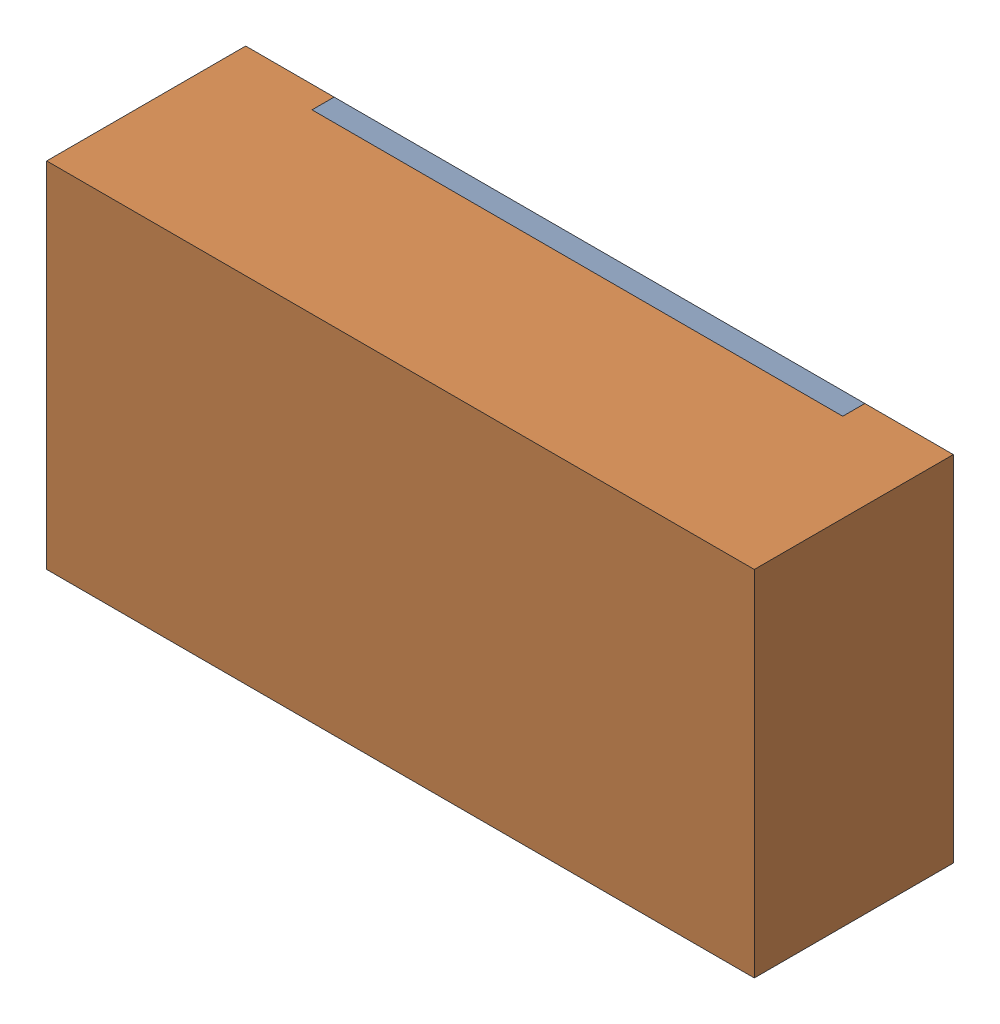
SolidWorks assembly RC2, configuration 默认. Lengths in mm.
Overall size (1.6 0.8 0.45).
3 component instances, 2 part files, 0 mates.
Components (placement in the parent):
- RC2-subassembly-1-1: RC2-subassembly-1 [默认] at (36.5761 12.3189 -1.6914) x (1 0 0) z (0 0 -1) size (1.6 0.8 0.45)
  - R0603-1: R0603 [默认] at origin size (1.2 0.8 0.05)
  - R0603-1-1: R0603-1 [默认] at origin size (1.6 0.8 0.45)
